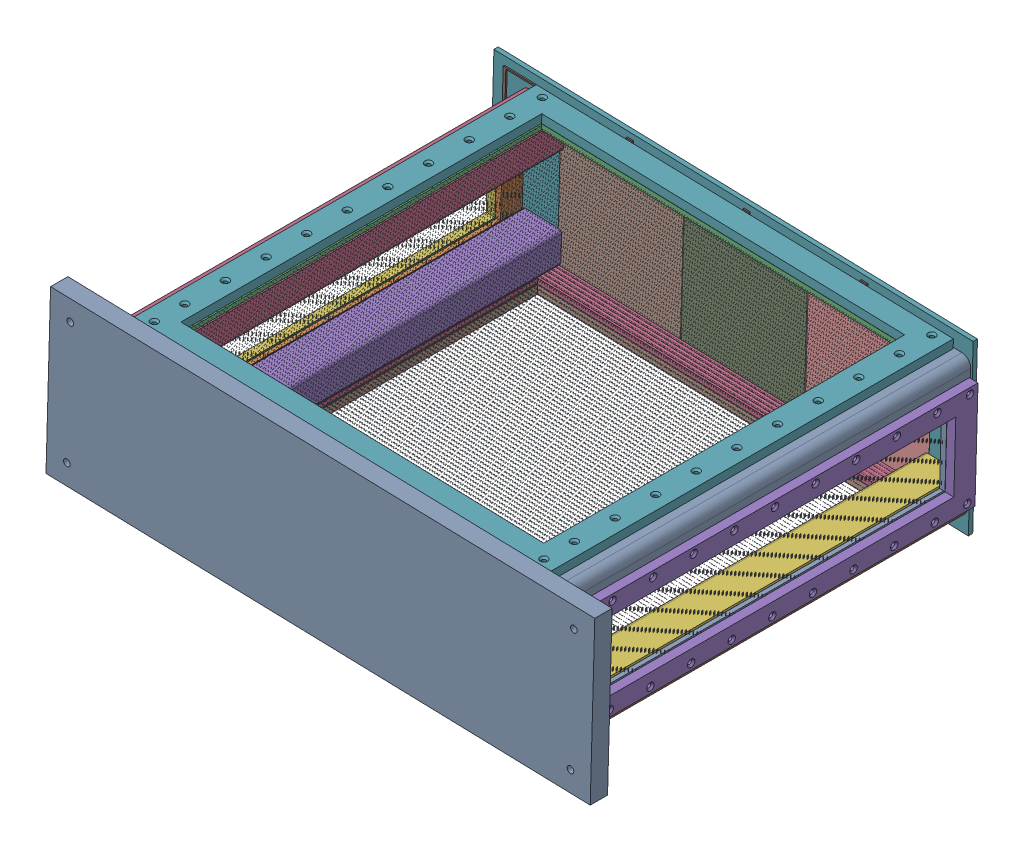
SolidWorks assembly TPC, configuration Default. Lengths in mm.
Overall size (405.22 136.02 329.34).
29 component instances, 15 part files, 0 mates.
Components (placement in the parent):
- fieldCage-1: fieldCage [Default] at (14.2049 -25.4834 -163.7333) x (0.999611 -0.027887 0) z (0 0 1) size (402 121.2 329.33)
  - FieldCage_Base-1: FieldCage_Base [Default] at (-19.1849 1.3046 -5) size (402 121.2 12.8)
  - FieldCage_Cathode-1: FieldCage_Cathode [Default] at (-19.1849 1.3046 -5) x (1 0 0) z (0 0 -1) size (344 113.2 0.03)
  - FieldCage_Pillar-1: FieldCage_Pillar [Default] at (128.8151 38.9046 -305.035) size (28 22.3 322.8)
  - FieldCage_Pillar_1-1: FieldCage_Pillar_1 [Default] at (-167.1849 38.9046 -305.035) x (0 1 0) z (0 0 1) size (22.3 28 322.8)
  - FieldCage_Pillar-2: FieldCage_Pillar [Default] at (-167.1849 -36.2954 -305.035) x (-1 0 0) z (0 0 1) size (28 22.3 322.8)
  - FieldCage_Pillar_1-2: FieldCage_Pillar_1 [Default] at (128.8151 -36.2954 -305.035) x (0 -1 0) z (0 0 1) size (22.3 28 322.8)
- GEM_assembly-1: GEM_assembly [Default] at (1.914 -18.6009 -469.9333) x (0.999611 -0.027887 0) z (0 0 1) size (354 126.2 4.2)
  - GEM_PCB-1: GEM_PCB [Default] at (-6.7068 -5.2326 -2.5) size (354 126.2 3.2)
  - GEM _10x10-1: GEM _10x10 [Default] at (-98.2068 -5.2326 0.75) x (0 -1 0) z (0 0 -1) size (106.2 91 0.05)
  - GEM _10x10-2: GEM _10x10 [Default] at (-6.821 -5.2326 0.75) x (0 1 0) z (0 0 -1) size (106.2 91 0.05)
  - GEM _10x10-3: GEM _10x10 [Default] at (84.7932 -5.2326 0.75) x (0 1 0) z (0 0 -1) size (106.2 91 0.05)
  - GEM_connection-1: GEM_connection [Default] at (-6.7068 -5.2326 1.7) x (1 0 0) z (0 0 -1) size (269.98 118.27 1)
- innerWire-1: innerWire [Default] at (161.1492 -28.2777 -318.5183) x (0.027887 0.999611 0) z (-0.999611 0.027887 0) size (80 298.5 4.12)
- innerWire-2: innerWire [Default] at (-171.0215 -19.011 -318.5183) x (-0.027887 -0.999611 0) z (0.999611 -0.027887 0) size (80 298.5 4.12)
- innerWire_1-1: innerWire_1 [Default] at (-3.4846 28.3854 -318.5183) x (-0.999611 0.027887 0) z (-0.027887 -0.999611 0) size (308 298.5 4.12)
- innerWire_1-2: innerWire_1 [Default] at (-6.3877 -75.6741 -318.5183) x (0.999611 -0.027887 0) z (0.027887 0.999611 0) size (308 298.5 4.12)
- innerWire_2-1: innerWire_2 [Default] at (167.6967 -28.4604 -318.5183) x (0.027887 0.999611 0) z (-0.999611 0.027887 0) size (80 298.5 6.53)
- innerWire_2-2: innerWire_2 [Default] at (-177.569 -18.8283 -318.5183) x (-0.027887 -0.999611 0) z (0.999611 -0.027887 0) size (80 298.5 6.53)
- innerWire_3-1: innerWire_3 [Default] at (-3.302 34.9329 -318.5183) x (-0.999611 0.027887 0) z (-0.027887 -0.999611 0) size (308 298.5 6.53)
- innerWire_3-2: innerWire_3 [Default] at (-6.5703 -82.2216 -318.5183) x (0.999611 -0.027887 0) z (0.027887 0.999611 0) size (308 298.5 6.53)
- FieldCage_FPC1-1: FieldCage_FPC1 [Default] at (155.7679 17.2901 -468.7683) x (0.999611 -0.027887 0) z (0 0 1) size (27.55 21.85 300)
- FieldCage_FPC1_1-1: FieldCage_FPC1_1 [Default] at (153.2358 -73.4746 -468.7683) x (-0.027887 -0.999611 0) z (0 0 1) size (21.85 27.55 300)
- FieldCage_FPC1-2: FieldCage_FPC1 [Default] at (-165.6402 -64.5788 -468.7683) x (-0.999611 0.027887 0) z (0 0 1) size (27.55 21.85 300)
- FieldCage_FPC1_1-2: FieldCage_FPC1_1 [Default] at (-163.1081 26.1859 -468.7683) x (0.027887 0.999611 0) z (0 0 1) size (21.85 27.55 300)
- FieldCage_FPC2-1: FieldCage_FPC2 [Default] at (155.7679 17.2901 -468.7683) x (0.999611 -0.027887 0) z (0 0 1) size (31.7 26 300)
- FieldCage_FPC2_1-1: FieldCage_FPC2_1 [Default] at (153.2358 -73.4746 -468.7683) x (-0.027887 -0.999611 0) z (0 0 1) size (26 31.7 300)
- FieldCage_FPC2-2: FieldCage_FPC2 [Default] at (-165.6402 -64.5788 -468.7683) x (-0.999611 0.027887 0) z (0 0 1) size (31.7 26 300)
- FieldCage_FPC2_1-2: FieldCage_FPC2_1 [Default] at (-163.1081 26.1859 -468.7683) x (0.027887 0.999611 0) z (0 0 1) size (26 31.7 300)
